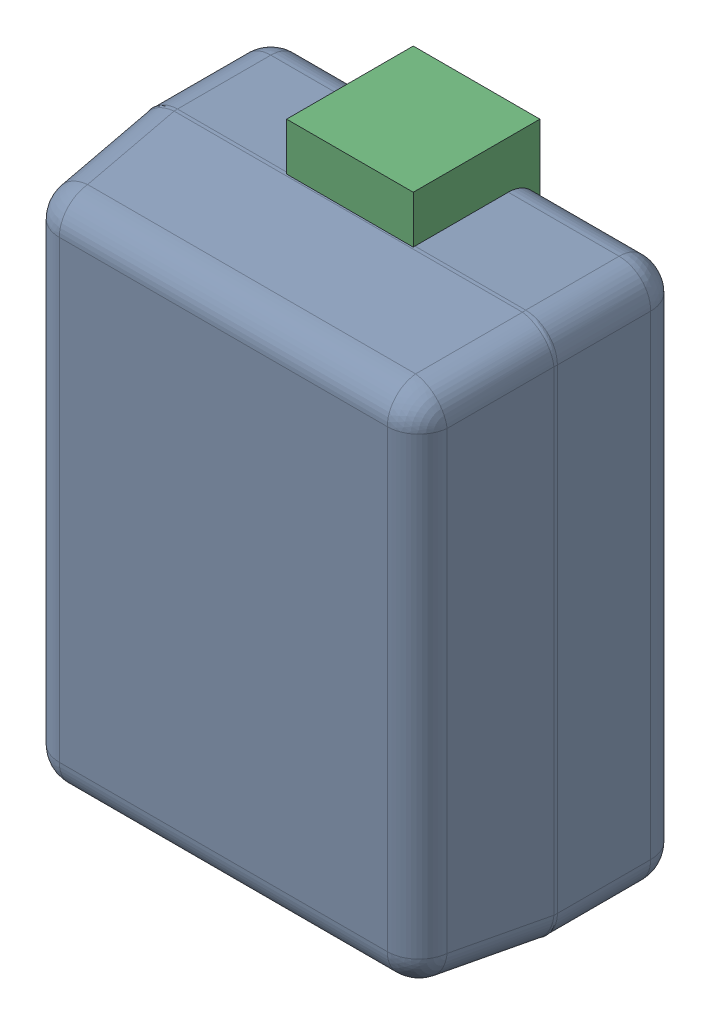
SolidWorks assembly D81.step, configuration Default. Lengths in mm.
Overall size (0.66 1 0.4).
5 component instances, 2 part files, 0 mates.
Components (placement in the parent):
- 6297722768.step-1: 6297722768.step [Default] at (25.4254 -1.9844 0) x (0 1 0) z (0 0 1) size (1 0.66 0.4)
  - Body (8).step-1: Body (8).step [Default] at (-0.425 -0.325 0) size (0.85 0.66 0.4)
    - Open CASCADE STEP translator 6.8 15.1.1.step-1: Open CASCADE STEP translator 6.8 15.1.1.step [Default] at origin size (0.85 0.66 0.4)
  - lead.step-1: lead.step [Default] at (-0.5 -0.1 0) size (0.19 0.2 0.2)
  - lead.step-2: lead.step [Default] at (0.5 0.1 0) x (-1 0 0) z (0 0 1) size (0.19 0.2 0.2)
